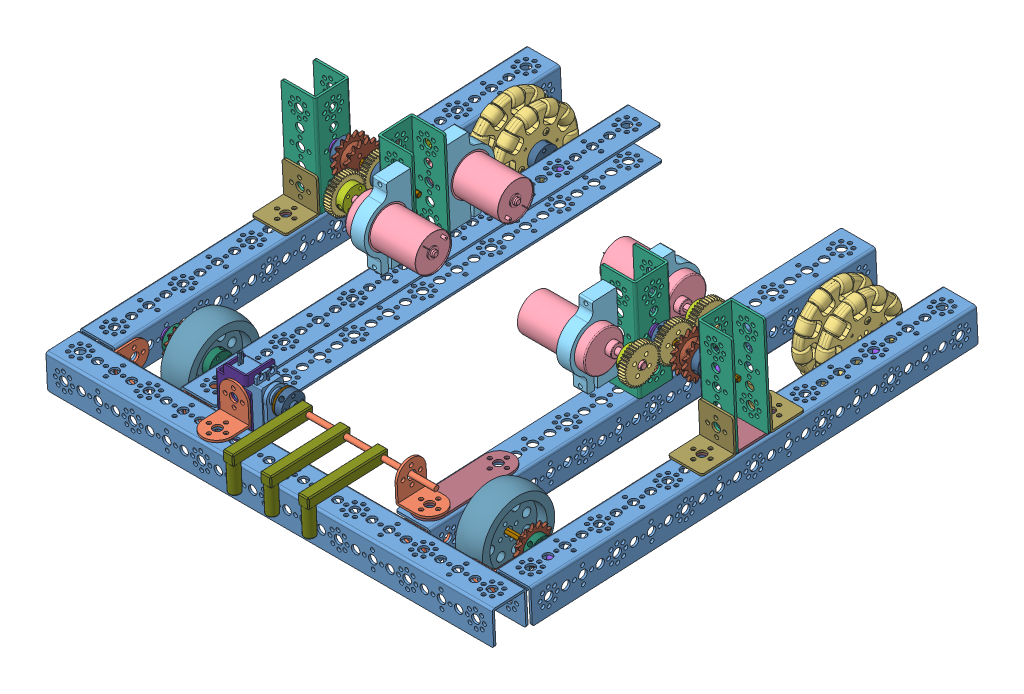
SolidWorks assembly Base Assembly, configuration Default. Lengths in mm.
Overall size (487.76 214.94 471.57).
98 component instances, 22 part files, 130 mates.
Components (placement in the parent):
- Tetrix 416mm-1: Tetrix 416mm [Default] at (441.3728 409.8855 6.1212) x (1 0 0) z (0 -0.047991 0.998848) size (32 32 416)
- Tetrix 416mm-2: Tetrix 416mm [Default] at (347.3728 409.8855 6.1212) x (0 -0.998848 -0.047991) z (0 -0.047991 0.998848) size (32 32 416)
- Tetrix 416mm-3: Tetrix 416mm [Default] at (53.3728 409.8855 6.1212) x (1 0 0) z (0 -0.047991 0.998848) size (32 32 416)
- Tetrix 416mm-4: Tetrix 416mm [Default] at (147.3728 409.8855 6.1212) x (0 0.998848 0.047991) z (0 -0.047991 0.998848) size (32 32 416)
- Tetrix 416mm-5: Tetrix 416mm [Default] at (455.3728 409.0217 24.1004) x (0 0.047991 -0.998848) z (1 0 0) size (32 32 416)
- Tetrix Angle Bracket-1: Tetrix Angle Bracket [Default] at (403.8982 411.5068 -11.8601) x (0 0.998848 0.047991) z (0 -0.047991 0.998848) size (27 31.5 31.5)
- Tetrix Angle Bracket-2: Tetrix Angle Bracket [Default] at (339.8982 411.5068 -11.8601) x (0 0.998848 0.047991) z (0 -0.047991 0.998848) size (27 31.5 31.5)
- Tetrix Angle Bracket-3: Tetrix Angle Bracket [Default] at (90.8475 409.9956 -11.9327) x (0 -0.998848 -0.047991) z (0 -0.047991 0.998848) size (27 31.5 31.5)
- Tetrix Angle Bracket-4: Tetrix Angle Bracket [Default] at (154.8475 409.9956 -11.9327) x (0 -0.998848 -0.047991) z (0 -0.047991 0.998848) size (27 31.5 31.5)
- Base Gearbox-3: Base Gearbox [Default] at (-255.1905 248.791 -250.3559) x (0.93253 -0.360659 -0.017662) z (-0.011317 -0.078079 0.996883) size (179.16 136.45 124.21)
  - Gear Metric 40T-5: Gear Metric 40T [PreviewCfg] at (251.3927 353.961 -2.865) x (0.93253 0.360914 -0.011317) z (-0.302942 0.799028 0.519404) size (6.2 33.53 33.53)
  - Gear Metric 40T-6: Gear Metric 40T [PreviewCfg] at (251.3714 356.0218 61.1018) x (0.93253 0.360914 -0.011317) z (0.242761 -0.649832 -0.720268) size (6.2 33.53 33.53)
  - DC gearhead motor-1: DC gearhead motor [Default] at (298.6742 372.0501 -9.9354) x (0.361091 -0.932043 0.030148) z (0.000333 -0.0322 -0.999481) size (37 98.8 37)
  - DC gearhead motor-2: DC gearhead motor [Default] at (298.6485 374.5295 67.0247) x (-0.361091 0.932043 -0.030148) z (-0.000333 0.0322 0.999481) size (37 98.8 37)
  - Tetrix Motor Mount-5: Tetrix Motor Mount [Default] at (291.2273 357.2311 -9.3463) x (-0.361091 0.932043 -0.030148) z (-0.93253 -0.360914 0.011317) size (72 44.98 12.7)
  - Tetrix Motor Mount-6: Tetrix Motor Mount [Default] at (302.2979 363.9977 67.2511) x (-0.361091 0.932043 -0.030148) z (0.93253 0.360914 -0.011317) size (72 44.98 12.7)
  - Tetrix 96mm-1: Tetrix 96mm [Default] at (302.6119 323.3726 30.1542) x (-0.000333 0.0322 0.999481) z (0.361091 -0.932043 0.030148) size (32 32 96)
  - Hub motor shaft-5: Hub motor shaft [Default] at (257.1744 356.1987 -2.9351) x (-0.196503 0.480932 -0.854454) z (-0.93253 -0.360914 0.011317) size (22 22 9.5)
  - Hub motor shaft-6: Hub motor shaft [Default] at (257.1531 358.2595 61.0317) x (0.267309 -0.668924 0.693604) z (-0.93253 -0.360914 0.011317) size (22 22 9.5)
  - Tetrix 96mm-3: Tetrix 96mm [Default] at (184.0194 380.3664 28.2785) x (-0.000333 0.0322 0.999481) z (-0.361091 0.932043 -0.030148) size (32 32 96)
  - Axle bronze bushing-21: Axle bronze bushing [Default] at (217.5778 341.9083 29.5287) x (0.165216 -0.398599 0.902121) z (0.93253 0.360914 -0.011317) size (11 11 12.4)
  - Axle bronze bushing-22: Axle bronze bushing [Default] at (269.0535 361.8307 28.904) x (0.124395 -0.291672 0.948395) z (-0.93253 -0.360914 0.011317) size (11 11 12.4)
  - Tetrix 4.7mm Axle-14: Tetrix 4.7mm Axle [Default] at (289.9422 369.9152 28.6505) x (0.124395 -0.291672 0.948395) z (-0.93253 -0.360914 0.011317) size (4.7 4.3 100)
  - Gear Metric 40T-17: Gear Metric 40T [PreviewCfg] at (251.3821 354.9914 29.1184) x (0.93253 0.360914 -0.011317) z (0.105307 -0.241847 0.964583) size (6.2 33.53 33.53)
  - Hub axle shaft-27: Hub axle shaft [Default] at (257.1637 357.2291 29.0483) x (0.140118 -0.332797 0.93253) z (-0.93253 -0.360914 0.011317) size (22 22 9.5)
  - Tetrix 16T Sprocket-7: Tetrix 16T Sprocket [Default] at (238.5598 350.0289 29.274) x (0.140118 -0.332797 0.93253) z (-0.93253 -0.360914 0.011317) size (36 36 6.8)
  - Tetrix 16T Sprocket-8: Tetrix 16T Sprocket [Default] at (231.0995 347.1415 29.3646) x (-0.140118 0.332797 -0.93253) z (0.93253 0.360914 -0.011317) size (36 36 6.8)
  - Hub axle shaft-28: Hub axle shaft [Default] at (228.4884 346.131 29.3963) x (0.140118 -0.332797 0.93253) z (0.93253 0.360914 -0.011317) size (22 22 9.5)
  - Tetrix Square Angle Bracket-1: Tetrix Square Angle Bracket [Default] at (212.9174 304.7726 -1.2931) x (-0.93253 -0.360914 0.011317) z (0.000333 -0.0322 -0.999481) size (32 32 32)
  - Tetrix Square Angle Bracket-2: Tetrix Square Angle Bracket [Default] at (212.8961 306.8334 62.6737) x (0.93253 0.360914 -0.011317) z (-0.000333 0.0322 0.999481) size (32 32 32)
  - Bracket flat-1: Bracket flat [Default] at (219.0453 289.9583 31.2028) x (0.000333 -0.0322 -0.999481) z (0.93253 0.360914 -0.011317) size (91 2 27)
  - Tetrix Angle Bracket-13: Tetrix Angle Bracket [Default] at (301.2105 343.7275 30.2548) x (-0.000333 0.0322 0.999481) z (-0.93253 -0.360914 0.011317) size (27 31.5 31.5)
- Base Gearbox-4: Base Gearbox [Default] at (749.9361 244.9085 -169.5482) x (-0.93253 -0.360691 -0.016997) z (0.011317 0.017853 -0.999777) size (179.16 136.45 124.21)
  - Gear Metric 40T-5: Gear Metric 40T [PreviewCfg] at (251.3927 353.961 -2.865) x (0.93253 0.360914 -0.011317) z (-0.302942 0.799028 0.519404) size (6.2 33.53 33.53)
  - Gear Metric 40T-6: Gear Metric 40T [PreviewCfg] at (251.3714 356.0218 61.1018) x (0.93253 0.360914 -0.011317) z (0.242761 -0.649832 -0.720268) size (6.2 33.53 33.53)
  - DC gearhead motor-1: DC gearhead motor [Default] at (298.6742 372.0501 -9.9354) x (0.361091 -0.932043 0.030148) z (0.000333 -0.0322 -0.999481) size (37 98.8 37)
  - DC gearhead motor-2: DC gearhead motor [Default] at (298.6485 374.5295 67.0247) x (-0.361091 0.932043 -0.030148) z (-0.000333 0.0322 0.999481) size (37 98.8 37)
  - Tetrix Motor Mount-5: Tetrix Motor Mount [Default] at (291.2273 357.2311 -9.3463) x (-0.361091 0.932043 -0.030148) z (-0.93253 -0.360914 0.011317) size (72 44.98 12.7)
  - Tetrix Motor Mount-6: Tetrix Motor Mount [Default] at (302.2979 363.9977 67.2511) x (-0.361091 0.932043 -0.030148) z (0.93253 0.360914 -0.011317) size (72 44.98 12.7)
  - Tetrix 96mm-1: Tetrix 96mm [Default] at (302.6119 323.3726 30.1542) x (-0.000333 0.0322 0.999481) z (0.361091 -0.932043 0.030148) size (32 32 96)
  - Hub motor shaft-5: Hub motor shaft [Default] at (257.1744 356.1987 -2.9351) x (-0.196503 0.480932 -0.854454) z (-0.93253 -0.360914 0.011317) size (22 22 9.5)
  - Hub motor shaft-6: Hub motor shaft [Default] at (257.1531 358.2595 61.0317) x (0.267309 -0.668924 0.693604) z (-0.93253 -0.360914 0.011317) size (22 22 9.5)
  - Tetrix 96mm-3: Tetrix 96mm [Default] at (184.0194 380.3664 28.2785) x (-0.000333 0.0322 0.999481) z (-0.361091 0.932043 -0.030148) size (32 32 96)
  - Axle bronze bushing-21: Axle bronze bushing [Default] at (217.5778 341.9083 29.5287) x (0.165216 -0.398599 0.902121) z (0.93253 0.360914 -0.011317) size (11 11 12.4)
  - Axle bronze bushing-22: Axle bronze bushing [Default] at (269.0535 361.8307 28.904) x (0.124395 -0.291672 0.948395) z (-0.93253 -0.360914 0.011317) size (11 11 12.4)
  - Tetrix 4.7mm Axle-14: Tetrix 4.7mm Axle [Default] at (289.9422 369.9152 28.6505) x (0.124395 -0.291672 0.948395) z (-0.93253 -0.360914 0.011317) size (4.7 4.3 100)
  - Gear Metric 40T-17: Gear Metric 40T [PreviewCfg] at (251.3821 354.9914 29.1184) x (0.93253 0.360914 -0.011317) z (0.105307 -0.241847 0.964583) size (6.2 33.53 33.53)
  - Hub axle shaft-27: Hub axle shaft [Default] at (257.1637 357.2291 29.0483) x (0.140118 -0.332797 0.93253) z (-0.93253 -0.360914 0.011317) size (22 22 9.5)
  - Tetrix 16T Sprocket-7: Tetrix 16T Sprocket [Default] at (238.5598 350.0289 29.274) x (0.140118 -0.332797 0.93253) z (-0.93253 -0.360914 0.011317) size (36 36 6.8)
  - Tetrix 16T Sprocket-8: Tetrix 16T Sprocket [Default] at (231.0995 347.1415 29.3646) x (-0.140118 0.332797 -0.93253) z (0.93253 0.360914 -0.011317) size (36 36 6.8)
  - Hub axle shaft-28: Hub axle shaft [Default] at (228.4884 346.131 29.3963) x (0.140118 -0.332797 0.93253) z (0.93253 0.360914 -0.011317) size (22 22 9.5)
  - Tetrix Square Angle Bracket-1: Tetrix Square Angle Bracket [Default] at (212.9174 304.7726 -1.2931) x (-0.93253 -0.360914 0.011317) z (0.000333 -0.0322 -0.999481) size (32 32 32)
  - Tetrix Square Angle Bracket-2: Tetrix Square Angle Bracket [Default] at (212.8961 306.8334 62.6737) x (0.93253 0.360914 -0.011317) z (-0.000333 0.0322 0.999481) size (32 32 32)
  - Bracket flat-1: Bracket flat [Default] at (219.0453 289.9583 31.2028) x (0.000333 -0.0322 -0.999481) z (0.93253 0.360914 -0.011317) size (91 2 27)
  - Tetrix Angle Bracket-13: Tetrix Angle Bracket [Default] at (301.2105 343.7275 30.2548) x (-0.000333 0.0322 0.999481) z (-0.93253 -0.360914 0.011317) size (27 31.5 31.5)
- Wheel 76mm 3-in-1: Wheel 76mm 3-in [Default] at (374.1068 412.1891 -41.8235) x (0 0.924225 0.381849) z (-1 0 0) size (72.2 72.2 25.4)
- Axle bronze bushing-1: Axle bronze bushing [Default] at (364.7728 426.7783 -345.4732) x (0 0 -1) z (1 0 0) size (11 11 12.4)
- Tetrix 4.7mm Axle Hub-1: Tetrix 4.7mm Axle Hub [Default] at (412.2728 412.1891 -41.8235) x (0 0 1) z (-1 0 0) size (22 22 9.4)
- Tetrix 4.7mm Axle Hub-2: Tetrix 4.7mm Axle Hub [Default] at (82.4728 412.1891 -41.8235) x (0 0 -1) z (1 0 0) size (22 22 9.4)
- Tetrix 4.7mm Axle Hub-3: Tetrix 4.7mm Axle Hub [Default] at (381.4728 412.1891 -41.8235) x (0 0.924225 0.381849) z (1 0 0) size (22 22 9.4)
- Tetrix 4.7mm Axle Hub-4: Tetrix 4.7mm Axle Hub [Default] at (113.2728 412.1891 -41.8235) x (0 0.924225 0.381849) z (-1 0 0) size (22 22 9.4)
- Tetrix 4.7mm Axle-1: Tetrix 4.7mm Axle [Default] at (346.3728 426.7783 -345.4732) x (0 0 -1) z (1 0 0) size (4.7 4.3 100)
- Tetrix 4.7mm Axle-2: Tetrix 4.7mm Axle [Default] at (48.3728 426.7783 -345.4732) x (0 0 -1) z (1 0 0) size (4.7 4.3 100)
- Tetrix 4.7mm Axle-3: Tetrix 4.7mm Axle [Default] at (48.3728 412.1891 -41.8235) x (0 0 -1) z (1 0 0) size (4.7 4.3 100)
- Tetrix 4.7mm Axle-4: Tetrix 4.7mm Axle [Default] at (446.3728 412.1891 -41.8235) x (0 0 1) z (-1 0 0) size (4.7 4.3 100)
- Axle bronze bushing-2: Axle bronze bushing [Default] at (70.7728 412.1891 -41.8235) x (0 0 -1) z (1 0 0) size (11 11 12.4)
- Axle bronze bushing-3: Axle bronze bushing [Default] at (423.9728 426.7783 -345.4732) x (0 0 1) z (-1 0 0) size (11 11 12.4)
- Axle bronze bushing-4: Axle bronze bushing [Default] at (423.9728 412.1891 -41.8235) x (0 0 1) z (-1 0 0) size (11 11 12.4)
- Axle bronze bushing-5: Axle bronze bushing [Default] at (129.9728 412.1891 -41.8235) x (0 0 1) z (-1 0 0) size (11 11 12.4)
- Axle bronze bushing-6: Axle bronze bushing [Default] at (70.7728 426.7783 -345.4732) x (0 0 -1) z (1 0 0) size (11 11 12.4)
- Axle bronze bushing-7: Axle bronze bushing [Default] at (364.7728 412.1891 -41.8235) x (0 0 -1) z (1 0 0) size (11 11 12.4)
- Axle bronze bushing-8: Axle bronze bushing [Default] at (129.9728 426.7783 -345.4732) x (0 0 1) z (-1 0 0) size (11 11 12.4)
- Wheel 76mm 3-in-2: Wheel 76mm 3-in [Default] at (99.5568 412.1891 -41.8235) x (0 0.381849 -0.924225) z (-1 0 0) size (72.2 72.2 25.4)
- Tetrix 16T Sprocket-2: Tetrix 16T Sprocket [Default] at (409.4728 412.1891 -41.8235) x (0 0 1) z (-1 0 0) size (36 36 6.8)
- Tetrix 16T Sprocket-4: Tetrix 16T Sprocket [Default] at (85.2728 412.1891 -41.8235) x (0 0 -1) z (1 0 0) size (36 36 6.8)
- Goal Hook-1: Goal Hook [Default] at (234.3728 451.6043 -13.5212) x (0 0.043619 -0.999048) z (-1 0 0) size (75 35 10)
- Goal Hook-2: Goal Hook [Default] at (304.3728 451.6043 -13.5212) x (0 0.043619 -0.999048) z (-1 0 0) size (75 35 10)
- Goal Hook-3: Goal Hook [Default] at (269.3728 451.6043 -13.5212) x (0 0.043619 -0.999048) z (-1 0 0) size (75 35 10)
- Bracket servo single-1: Bracket servo single [Default] at (183.3728 435.8556 7.3689) x (0 -0.998848 -0.047991) z (1 0 0) size (60 26.6 32.67)
- Servo metal horn-1: Servo metal horn [Default] at (211.7728 446.391 -8.744) x (0 -1 0) z (0 0 1) size (22.2 6.2 22.2)
- Servo motor HS475-1: Servo motor HS475 [Default] at (193.9728 446.391 -8.744) x (0 -0.047991 0.998848) z (0 0.998848 0.047991) size (20 43.2 56.6)
- Hub axle shaft-5: Hub axle shaft [Default] at (220.4728 446.391 -8.744) x (0 0 -1) z (1 0 0) size (22 22 9.5)
- Axle D-shaft-1: Axle D-shaft [Default] at (283.7728 446.391 -8.744) x (0 0.043619 -0.999048) z (-1 0 0) size (4.73 4.46 140)
- Tetrix Angle Bracket-6: Tetrix Angle Bracket [Default] at (182.6164 446.3553 27.9349) x (-1 0 0) z (0 0.047991 -0.998848) size (27 31.5 31.5)
- Tetrix Angle Bracket-7: Tetrix Angle Bracket [Default] at (349.4112 450.0462 -7.2104) x (0 -0.047991 0.998848) z (-1 0 0) size (27 31.5 31.5)
- Bracket flat-1: Bracket flat [Default] at (347.3728 429.1695 -41.0077) x (0 -0.047991 0.998848) z (-1 0 0) size (91 2 27)
- Omni Wheels-1: Omni Wheels [Default] at (39.7243 394.7419 -398.5232) x (0 -0.381849 0.924225) z (0 0.924225 0.381849) size (77.7 40.21 77.72)
  - 3-inch omni single wheel part-1: 3-inch omni single wheel part [Default] at (43.8688 43.474 49.8315) size (77.7 13.48 77.72)
  - 3-inch omni single wheel part-2: 3-inch omni single wheel part [Default] at (43.8688 71.023 49.9004) x (1 0 0) z (0 0 -1) size (77.7 13.48 77.72)
  - Omni wheel joining hub-1: Omni wheel joining hub [Default] at (36.7969 53.8485 49.866) x (1 0 0) z (0 1 0) size (22 22 5)
  - Tetrix 16T Sprocket-1: Tetrix 16T Sprocket [Default] at (36.7969 59.1485 49.866) x (0.987505 0 -0.157585) z (0 1 0) size (36 36 6.8)
  - Hub axle shaft-1: Hub axle shaft [Default] at (36.7969 73.1485 49.866) x (0.987505 0 0.157585) z (0 -1 0) size (22 22 9.5)
- Omni Wheels-2: Omni Wheels [Default] at (457.8214 389.9814 -395.3392) x (0 1 0) z (0 0 1) size (77.7 40.21 77.72)
  - 3-inch omni single wheel part-1: 3-inch omni single wheel part [Default] at (43.8688 43.474 49.8315) size (77.7 13.48 77.72)
  - 3-inch omni single wheel part-2: 3-inch omni single wheel part [Default] at (43.8688 71.023 49.9004) x (1 0 0) z (0 0 -1) size (77.7 13.48 77.72)
  - Omni wheel joining hub-1: Omni wheel joining hub [Default] at (36.7969 53.8485 49.866) x (1 0 0) z (0 1 0) size (22 22 5)
  - Tetrix 16T Sprocket-1: Tetrix 16T Sprocket [Default] at (36.7969 59.1485 49.866) x (0.987505 0 -0.157585) z (0 1 0) size (36 36 6.8)
  - Hub axle shaft-1: Hub axle shaft [Default] at (36.7969 73.1485 49.866) x (0.987505 0 0.157585) z (0 -1 0) size (22 22 9.5)
Mates (geometry in assembly coordinates):
- Coincident1: coincident anti-aligned: plane of Tetrix 416mm-5 through (39.3728 425.7711 8.8867) normal (0 0.047991 -0.998848); plane of Tetrix Angle Bracket-1 through (393.8728 396.3051 7.471) normal (0 -0.047991 0.998848)
- Concentric1: concentric anti-aligned: cylinder of Tetrix 416mm-5 through (407.3728 408.2538 40.082) axis (0 0.047991 -0.998848) radius 4; cylinder of Tetrix Angle Bracket-1 through (407.3728 411.3013 -23.3448) axis (0 -0.047991 0.998848) radius 4
- Concentric2: concentric anti-aligned: cylinder of Tetrix 416mm-5 through (415.3728 408.2538 40.082) axis (0 0.047991 -0.998848) radius 1.85; cylinder of Tetrix Angle Bracket-1 through (415.3728 411.3013 -23.3448) axis (0 -0.047991 0.998848) radius 1.85
- Coincident2: coincident anti-aligned: plane of Tetrix 416mm-1 through (425.3728 445.8313 -408.6316) normal (-1 0 0); plane of Tetrix Angle Bracket-1 through (425.3728 396.3051 7.471) normal (1 0 0)
- Concentric3: concentric aligned: cylinder of Tetrix 416mm-1 through (425.3728 410.6534 -9.8604) axis (1 0 0) radius 4; cylinder of Tetrix Angle Bracket-1 through (393.8728 410.6534 -9.8604) axis (1 0 0) radius 4
- Concentric4: concentric aligned: cylinder of Tetrix 416mm-1 through (425.3728 411.0373 -17.8512) axis (1 0 0) radius 1.85; cylinder of Tetrix Angle Bracket-1 through (393.8728 411.0373 -17.8512) axis (1 0 0) radius 1.85
- Coincident5: coincident anti-aligned: plane of Tetrix 416mm-5 through (39.3728 425.7711 8.8867) normal (0 0.047991 -0.998848); plane of Tetrix Angle Bracket-2 through (329.8728 396.3051 7.471) normal (0 -0.047991 0.998848)
- Concentric11: concentric anti-aligned: cylinder of Tetrix 416mm-5 through (335.3728 408.2538 40.082) axis (0 0.047991 -0.998848) radius 1.85; cylinder of Tetrix Angle Bracket-2 through (335.3728 411.3013 -23.3448) axis (0 -0.047991 0.998848) radius 1.85
- Concentric13: concentric anti-aligned: cylinder of Tetrix 416mm-5 through (351.3728 408.2538 40.082) axis (0 0.047991 -0.998848) radius 1.85; cylinder of Tetrix Angle Bracket-2 through (351.3728 411.3013 -23.3448) axis (0 -0.047991 0.998848) radius 1.85
- Coincident6: coincident anti-aligned: plane of Tetrix 416mm-2 through (361.3728 443.8336 -408.7276) normal (-1 0 0); plane of Tetrix Angle Bracket-2 through (361.3728 396.3051 7.471) normal (1 0 0)
- Concentric14: concentric aligned: cylinder of Tetrix 416mm-2 through (331.3728 402.6626 -10.2443) axis (1 0 0) radius 1.85; cylinder of Tetrix Angle Bracket-2 through (329.8728 402.6626 -10.2443) axis (1 0 0) radius 1.85
- Concentric15: concentric aligned: cylinder of Tetrix 416mm-2 through (331.3728 418.6442 -9.4765) axis (1 0 0) radius 1.85; cylinder of Tetrix Angle Bracket-2 through (329.8728 418.6442 -9.4765) axis (1 0 0) radius 1.85
- Coincident7: coincident anti-aligned: plane of Tetrix 416mm-5 through (39.3728 425.7711 8.8867) normal (0 0.047991 -0.998848); plane of Tetrix Angle Bracket-3 through (100.8728 423.274 8.7667) normal (0 -0.047991 0.998848)
- Concentric16: concentric anti-aligned: cylinder of Tetrix 416mm-5 through (87.3728 408.2538 40.082) axis (0 0.047991 -0.998848) radius 4; cylinder of Tetrix Angle Bracket-3 through (87.3728 411.3013 -23.3448) axis (0 -0.047991 0.998848) radius 4
- Concentric17: concentric anti-aligned: cylinder of Tetrix 416mm-5 through (87.3728 416.2446 40.4659) axis (0 0.047991 -0.998848) radius 1.85; cylinder of Tetrix Angle Bracket-3 through (87.3728 419.292 -22.9609) axis (0 -0.047991 0.998848) radius 1.85
- Coincident8: coincident anti-aligned: plane of Tetrix 416mm-3 through (69.3728 445.8313 -408.6316) normal (1 0 0); plane of Tetrix Angle Bracket-3 through (69.3728 423.274 8.7667) normal (-1 0 0)
- Concentric18: concentric anti-aligned: cylinder of Tetrix 416mm-3 through (37.3728 410.6534 -9.8604) axis (1 0 0) radius 4; cylinder of Tetrix Angle Bracket-3 through (100.8728 410.6534 -9.8604) axis (-1 0 0) radius 4
- Concentric19: concentric anti-aligned: cylinder of Tetrix 416mm-3 through (37.3728 411.0373 -17.8512) axis (1 0 0) radius 1.85; cylinder of Tetrix Angle Bracket-3 through (100.8728 411.0373 -17.8512) axis (-1 0 0) radius 1.85
- Concentric21: concentric anti-aligned: cylinder of Tetrix 416mm-3 through (37.3728 410.2695 -1.8696) axis (1 0 0) radius 1.85; cylinder of Tetrix Angle Bracket-3 through (100.8728 410.2695 -1.8696) axis (-1 0 0) radius 1.85
- Coincident9: coincident anti-aligned: plane of Tetrix 416mm-5 through (39.3728 425.7711 8.8867) normal (0 0.047991 -0.998848); plane of Tetrix Angle Bracket-4 through (164.8728 423.274 8.7667) normal (0 -0.047991 0.998848)
- Concentric22: concentric anti-aligned: cylinder of Tetrix 416mm-5 through (151.3728 408.2538 40.082) axis (0 0.047991 -0.998848) radius 4; cylinder of Tetrix Angle Bracket-4 through (151.3728 411.3013 -23.3448) axis (0 -0.047991 0.998848) radius 4
- Concentric23: concentric anti-aligned: cylinder of Tetrix 416mm-5 through (143.3728 408.2538 40.082) axis (0 0.047991 -0.998848) radius 1.85; cylinder of Tetrix Angle Bracket-4 through (143.3728 411.3013 -23.3448) axis (0 -0.047991 0.998848) radius 1.85
- Coincident10: coincident anti-aligned: plane of Tetrix 416mm-4 through (133.3728 415.8659 -410.0714) normal (1 0 0); plane of Tetrix Angle Bracket-4 through (133.3728 423.274 8.7667) normal (-1 0 0)
- Concentric24: concentric aligned: cylinder of Tetrix 416mm-4 through (163.3728 410.6534 -9.8604) axis (-1 0 0) radius 4; cylinder of Tetrix Angle Bracket-4 through (164.8728 410.6534 -9.8604) axis (-1 0 0) radius 4
- Concentric25: concentric aligned: cylinder of Tetrix 416mm-4 through (163.3728 410.2695 -1.8696) axis (-1 0 0) radius 1.85; cylinder of Tetrix Angle Bracket-4 through (164.8728 410.2695 -1.8696) axis (-1 0 0) radius 1.85
- Coincident16: coincident anti-aligned: plane of Tetrix 416mm-3 through (43.0826 314.0125 -449.5638) normal (0 0.998848 0.047991); plane of ? through (77.0826 302.6146 -212.3374) normal (0 -0.998848 -0.047991)
- Concentric36: concentric anti-aligned: cylinder of Tetrix 416mm-3 through (59.0826 270.9154 -219.3668) axis (0 0.998848 0.047991) radius 1.85; cylinder of ? through (59.0826 334.3423 -216.3194) axis (0 -0.998848 -0.047991) radius 1.85
- Concentric37: concentric anti-aligned: cylinder of Tetrix 416mm-3 through (59.0826 271.6833 -235.3484) axis (0 0.998848 0.047991) radius 1.85; cylinder of ? through (59.0826 335.1101 -232.301) axis (0 -0.998848 -0.047991) radius 1.85
- Concentric38: concentric anti-aligned: cylinder of Tetrix 416mm-4 through (153.0826 270.9154 -219.3668) axis (0 0.998848 0.047991) radius 1.85; cylinder of ? through (153.0826 334.3423 -216.3194) axis (0 -0.998848 -0.047991) radius 1.85
- Concentric39: concentric anti-aligned: cylinder of Tetrix 416mm-4 through (153.0826 271.6833 -235.3484) axis (0 0.998848 0.047991) radius 1.85; cylinder of ? through (153.0826 335.1101 -232.301) axis (0 -0.998848 -0.047991) radius 1.85
- Coincident17: coincident anti-aligned: plane of Tetrix 416mm-1 through (431.0826 314.0125 -449.5638) normal (0 0.998848 0.047991); plane of ? through (429.0826 303.9104 -239.3063) normal (0 -0.998848 -0.047991)
- Concentric40: concentric aligned: cylinder of Tetrix 416mm-2 through (353.0826 303.2625 -225.8219) axis (0 -0.998848 -0.047991) radius 4; cylinder of ? through (353.0826 334.7262 -224.3102) axis (0 -0.998848 -0.047991) radius 4
- Concentric42: concentric aligned: cylinder of Tetrix 416mm-2 through (353.0826 302.8786 -217.8311) axis (0 -0.998848 -0.047991) radius 1.85; cylinder of ? through (353.0826 334.3423 -216.3194) axis (0 -0.998848 -0.047991) radius 1.85
- Concentric43: concentric anti-aligned: cylinder of Tetrix 416mm-1 through (447.0826 270.9154 -219.3668) axis (0 0.998848 0.047991) radius 1.85; cylinder of ? through (447.0826 334.3423 -216.3194) axis (0 -0.998848 -0.047991) radius 1.85
- Concentric44: concentric anti-aligned: cylinder of Tetrix 416mm-1 through (447.0826 271.6833 -235.3484) axis (0 0.998848 0.047991) radius 1.85; cylinder of ? through (447.0826 335.1101 -232.301) axis (0 -0.998848 -0.047991) radius 1.85
- Concentric45: concentric anti-aligned: cylinder of Tetrix 4.7mm Axle Hub-1 through (409.5728 412.1891 -41.8235) axis (1 0 0) radius 3.9625; cylinder of Tetrix 16T Sprocket-2 through (412.2728 412.1891 -41.8235) axis (-1 0 0) radius 4
- Coincident19: coincident anti-aligned: plane of Tetrix 4.7mm Axle Hub-1 through (412.2728 412.1891 -41.8235) normal (-1 0 0); plane of Tetrix 16T Sprocket-2 through (412.2728 428.4641 -41.8235) normal (1 0 0)
- Concentric46: concentric aligned: cylinder of Tetrix 4.7mm Axle Hub-1 through (418.9728 420.1891 -41.8235) axis (-1 0 0) radius 1.35; cylinder of Tetrix 16T Sprocket-2 through (412.2728 420.1891 -41.8235) axis (-1 0 0) radius 1.8
- Coincident20: coincident anti-aligned: plane of Tetrix 4.7mm Axle Hub-2 through (82.4728 412.1891 -41.8235) normal (1 0 0); plane of Tetrix 16T Sprocket-4 through (82.4728 428.4641 -41.8235) normal (-1 0 0)
- Concentric47: concentric anti-aligned: cylinder of Tetrix 4.7mm Axle Hub-2 through (85.1728 412.1891 -41.8235) axis (-1 0 0) radius 3.9625; cylinder of Tetrix 16T Sprocket-4 through (82.4728 412.1891 -41.8235) axis (1 0 0) radius 4
- Concentric48: concentric aligned: cylinder of Tetrix 4.7mm Axle Hub-2 through (75.7728 420.1891 -41.8235) axis (1 0 0) radius 1.35; cylinder of Tetrix 16T Sprocket-4 through (82.4728 420.1891 -41.8235) axis (1 0 0) radius 1.8
- Concentric49: concentric aligned: cylinder of Tetrix 416mm-2 through (331.3728 412.1891 -41.8235) axis (1 0 0) radius 4; cylinder of Axle bronze bushing-7 through (352.3728 412.1891 -41.8235) axis (1 0 0) radius 3.925
- Coincident21: coincident anti-aligned: plane of Tetrix 416mm-2 through (363.3728 445.8313 -408.6316) normal (1 0 0); plane of Axle bronze bushing-7 through (363.3728 412.1891 -41.8235) normal (-1 0 0)
- Concentric50: concentric anti-aligned: cylinder of Tetrix 416mm-1 through (425.3728 412.1891 -41.8235) axis (1 0 0) radius 4; cylinder of Axle bronze bushing-4 through (436.3728 412.1891 -41.8235) axis (-1 0 0) radius 3.925
- Coincident22: coincident anti-aligned: plane of Tetrix 416mm-1 through (425.3728 445.8313 -408.6316) normal (-1 0 0); plane of Axle bronze bushing-4 through (425.3728 412.1891 -41.8235) normal (1 0 0)
- Concentric51: concentric anti-aligned: cylinder of Tetrix 4.7mm Axle-4 through (346.3728 412.1891 -41.8235) axis (1 0 0) radius 2.35; cylinder of Axle bronze bushing-4 through (436.3728 412.1891 -41.8235) axis (-1 0 0) radius 2.4
- Distance1: distance = 10 mm aligned: plane of Tetrix 4.7mm Axle-4 through (446.3728 412.1891 -41.8235) normal (1 0 0); plane of Axle bronze bushing-4 through (436.3728 412.1891 -41.8235) normal (1 0 0)
- Coincident24: coincident anti-aligned: plane of Wheel 76mm 3-in-1 through (376.4728 412.1891 -41.8235) normal (-1 0 0); plane of Tetrix 4.7mm Axle Hub-3 through (376.4728 412.1891 -41.8235) normal (1 0 0)
- Concentric52: concentric aligned: cylinder of Wheel 76mm 3-in-1 through (392.3478 412.1891 -41.8235) axis (-1 0 0) radius 4; cylinder of Tetrix 4.7mm Axle Hub-3 through (379.1728 412.1891 -41.8235) axis (-1 0 0) radius 3.9625
- Concentric53: concentric anti-aligned: cylinder of Tetrix 4.7mm Axle Hub-4 through (110.5728 412.1891 -41.8235) axis (1 0 0) radius 3.9625; cylinder of Wheel 76mm 3-in-2 through (122.7978 412.1891 -41.8235) axis (-1 0 0) radius 4
- Coincident25: coincident anti-aligned: plane of Tetrix 4.7mm Axle Hub-4 through (113.2728 412.1891 -41.8235) normal (-1 0 0); plane of Wheel 76mm 3-in-2 through (113.2728 412.1891 -41.8235) normal (1 0 0)
- Concentric54: concentric aligned: cylinder of Tetrix 4.7mm Axle Hub-4 through (119.9728 415.2439 -49.2173) axis (-1 0 0) radius 1.35; cylinder of Wheel 76mm 3-in-2 through (122.7978 415.2439 -49.2173) axis (-1 0 0) radius 1.75
- Concentric55: concentric anti-aligned: cylinder of Wheel 76mm 3-in-1 through (392.3478 415.2439 -49.2173) axis (-1 0 0) radius 1.75; cylinder of Tetrix 4.7mm Axle Hub-3 through (369.7728 415.2439 -49.2173) axis (1 0 0) radius 1.35
- Distance4: distance = 10 mm anti-aligned: plane of Tetrix 4.7mm Axle Hub-3 through (374.7728 412.1891 -41.8235) normal (-1 0 0); plane of Axle bronze bushing-7 through (364.7728 412.1891 -41.8235) normal (1 0 0)
- Concentric58: concentric aligned: cylinder of Tetrix 4.7mm Axle Hub-3 through (369.7728 412.1891 -41.8235) axis (1 0 0) radius 2.365; cylinder of Tetrix 4.7mm Axle-4 through (346.3728 412.1891 -41.8235) axis (1 0 0) radius 2.35
- Concentric59: concentric anti-aligned: cylinder of Tetrix 4.7mm Axle Hub-1 through (418.9728 412.1891 -41.8235) axis (-1 0 0) radius 2.365; cylinder of Tetrix 4.7mm Axle-4 through (346.3728 412.1891 -41.8235) axis (1 0 0) radius 2.35
- Coincident29: coincident aligned: plane of ? through (418.6326 400.6307 -226.9639) normal (1 0 0); plane of Tetrix 16T Sprocket-2 through (418.6326 296.6452 -82.7557) normal (1 0 0)
- Concentric60: concentric aligned: cylinder of Tetrix 416mm-3 through (37.3728 412.1891 -41.8235) axis (1 0 0) radius 4; cylinder of Axle bronze bushing-2 through (58.3728 412.1891 -41.8235) axis (1 0 0) radius 3.925
- Coincident30: coincident anti-aligned: plane of Tetrix 416mm-3 through (69.3728 445.8313 -408.6316) normal (1 0 0); plane of Axle bronze bushing-2 through (69.3728 412.1891 -41.8235) normal (-1 0 0)
- Concentric61: concentric aligned: cylinder of Tetrix 416mm-4 through (163.3728 412.1891 -41.8235) axis (-1 0 0) radius 4; cylinder of Axle bronze bushing-5 through (142.3728 412.1891 -41.8235) axis (-1 0 0) radius 3.925
- Coincident31: coincident anti-aligned: plane of Tetrix 416mm-4 through (131.3728 413.8682 -410.1674) normal (-1 0 0); plane of Axle bronze bushing-5 through (131.3728 412.1891 -41.8235) normal (1 0 0)
- Concentric62: concentric anti-aligned: cylinder of Tetrix 4.7mm Axle-3 through (148.3728 412.1891 -41.8235) axis (-1 0 0) radius 2.35; cylinder of Axle bronze bushing-2 through (58.3728 412.1891 -41.8235) axis (1 0 0) radius 2.4
- Distance5: distance = 10 mm aligned: plane of Tetrix 4.7mm Axle-3 through (48.3728 412.1891 -41.8235) normal (-1 0 0); plane of Axle bronze bushing-2 through (58.3728 412.1891 -41.8235) normal (-1 0 0)
- Distance6: distance = 10 mm anti-aligned: plane of Tetrix 4.7mm Axle Hub-4 through (119.9728 412.1891 -41.8235) normal (1 0 0); plane of Axle bronze bushing-5 through (129.9728 412.1891 -41.8235) normal (-1 0 0)
- Concentric64: concentric aligned: cylinder of Tetrix 4.7mm Axle Hub-4 through (119.9728 412.1891 -41.8235) axis (-1 0 0) radius 2.365; cylinder of Tetrix 4.7mm Axle-3 through (148.3728 412.1891 -41.8235) axis (-1 0 0) radius 2.35
- Concentric65: concentric anti-aligned: cylinder of Tetrix 4.7mm Axle-3 through (148.3728 412.1891 -41.8235) axis (-1 0 0) radius 2.35; cylinder of Tetrix 16T Sprocket-4 through (82.4728 412.1891 -41.8235) axis (1 0 0) radius 4
- Coincident35: coincident aligned: plane of ? through (90.3326 389.747 -219.8785) normal (1 0 0); plane of Tetrix 16T Sprocket-4 through (90.3326 285.3702 -82.7557) normal (1 0 0)
- Concentric76: concentric aligned: cylinder of Tetrix 416mm-3 through (37.3728 426.7783 -345.4732) axis (1 0 0) radius 4; cylinder of Axle bronze bushing-6 through (58.3728 426.7783 -345.4732) axis (1 0 0) radius 3.925
- Coincident39: coincident anti-aligned: plane of Tetrix 416mm-3 through (69.3728 445.8313 -408.6316) normal (1 0 0); plane of Axle bronze bushing-6 through (69.3728 426.7783 -345.4732) normal (-1 0 0)
- Concentric77: concentric aligned: cylinder of Tetrix 416mm-4 through (163.3728 426.7783 -345.4732) axis (-1 0 0) radius 4; cylinder of Axle bronze bushing-8 through (142.3728 426.7783 -345.4732) axis (-1 0 0) radius 3.925
- Coincident40: coincident anti-aligned: plane of Tetrix 416mm-4 through (131.3728 413.8682 -410.1674) normal (-1 0 0); plane of Axle bronze bushing-8 through (131.3728 426.7783 -345.4732) normal (1 0 0)
- Concentric78: concentric anti-aligned: cylinder of Tetrix 4.7mm Axle-2 through (148.3728 426.7783 -345.4732) axis (-1 0 0) radius 2.35; cylinder of Axle bronze bushing-6 through (58.3728 426.7783 -345.4732) axis (1 0 0) radius 2.4
- Distance7: distance = 10 mm aligned: plane of Tetrix 4.7mm Axle-2 through (48.3728 426.7783 -345.4732) normal (-1 0 0); plane of Axle bronze bushing-6 through (58.3728 426.7783 -345.4732) normal (-1 0 0)
- Concentric88: concentric aligned: cylinder of Tetrix 416mm-2 through (331.3728 426.7783 -345.4732) axis (1 0 0) radius 4; cylinder of Axle bronze bushing-1 through (352.3728 426.7783 -345.4732) axis (1 0 0) radius 3.925
- Coincident48: coincident anti-aligned: plane of Tetrix 416mm-2 through (363.3728 445.8313 -408.6316) normal (1 0 0); plane of Axle bronze bushing-1 through (363.3728 426.7783 -345.4732) normal (-1 0 0)
- Concentric89: concentric anti-aligned: cylinder of Tetrix 416mm-1 through (425.3728 426.7783 -345.4732) axis (1 0 0) radius 4; cylinder of Axle bronze bushing-3 through (436.3728 426.7783 -345.4732) axis (-1 0 0) radius 3.925
- Coincident49: coincident anti-aligned: plane of Tetrix 416mm-1 through (425.3728 445.8313 -408.6316) normal (-1 0 0); plane of Axle bronze bushing-3 through (425.3728 426.7783 -345.4732) normal (1 0 0)
- Concentric90: concentric anti-aligned: cylinder of Axle bronze bushing-1 through (352.3728 426.7783 -345.4732) axis (1 0 0) radius 2.4; cylinder of Tetrix 4.7mm Axle-1 through (446.3728 426.7783 -345.4732) axis (-1 0 0) radius 2.35
- Distance10: distance = 10 mm aligned: plane of Tetrix 4.7mm Axle-1 through (446.3728 426.7783 -345.4732) normal (1 0 0); plane of Axle bronze bushing-3 through (436.3728 426.7783 -345.4732) normal (1 0 0)
- Coincident62: coincident anti-aligned: plane of Bracket servo single-1 through (193.9728 405.9669 4.3311) normal (1 0 0); plane of Servo motor HS475-1 through (193.9728 410.9535 -2.5626) normal (-1 0 0)
- Concentric103: concentric anti-aligned: cylinder of Bracket servo single-1 through (193.9728 460.6148 -13.0664) axis (1 0 0) radius 1.85; cylinder of Servo motor HS475-1 through (196.4728 460.6148 -13.0664) axis (-1 0 0) radius 2.15
- Concentric104: concentric anti-aligned: cylinder of Bracket servo single-1 through (193.9728 460.1349 -3.0779) axis (1 0 0) radius 1.85; cylinder of Servo motor HS475-1 through (196.4728 460.1349 -3.0779) axis (-1 0 0) radius 2.15
- Coincident63: coincident anti-aligned: plane of Bracket servo single-1 through (193.9728 405.9669 4.3311) normal (1 0 0); plane of Servo motor HS475-1 through (193.9728 410.9535 -2.5626) normal (-1 0 0)
- Concentric111: concentric aligned: cylinder of Servo metal horn-1 through (210.5728 446.391 -8.744) axis (-1 0 0) radius 2.85; cylinder of Servo motor HS475-1 through (210.5728 446.391 -8.744) axis (-1 0 0) radius 3
- Coincident65: coincident anti-aligned: plane of Servo metal horn-1 through (210.5728 446.391 -8.744) normal (-1 0 0); plane of Servo motor HS475-1 through (210.5728 446.391 -8.744) normal (1 0 0)
- Coincident66: coincident anti-aligned: plane of Servo metal horn-1 through (213.7728 446.391 -8.744) normal (1 0 0); plane of Hub axle shaft-5 through (213.7728 446.391 -8.744) normal (-1 0 0)
- Concentric113: concentric anti-aligned: cylinder of Servo metal horn-1 through (213.7728 446.391 -8.744) axis (-1 0 0) radius 1.75; cylinder of Hub axle shaft-5 through (213.7728 446.391 -8.744) axis (1 0 0) radius 2.3495
- Concentric116: concentric aligned: cylinder of Servo metal horn-1 through (211.7728 454.391 -8.744) axis (1 0 0) radius 1.75; cylinder of Hub axle shaft-5 through (220.4728 454.391 -8.744) axis (1 0 0) radius 1.3526
- Distance13: distance = 25 mm anti-aligned: plane of Goal Hook-3 through (269.3728 441.6138 -13.9574) normal (1 0 0); plane of Goal Hook-2 through (294.3728 441.6138 -13.9574) normal (-1 0 0)
- Distance14: distance = 25 mm anti-aligned: plane of Goal Hook-3 through (259.3728 441.6138 -13.9574) normal (-1 0 0); plane of Goal Hook-1 through (234.3728 441.6138 -13.9574) normal (1 0 0)
- Coincident71: coincident anti-aligned: plane of Servo metal horn-1 through (213.7728 446.391 -8.744) normal (1 0 0); plane of Axle D-shaft-1 through (213.7728 446.391 -8.744) normal (-1 0 0)
- Concentric121: concentric anti-aligned: cylinder of Hub axle shaft-5 through (213.7728 446.391 -8.744) axis (1 0 0) radius 2.3495; cylinder of Axle D-shaft-1 through (353.7728 446.391 -8.744) axis (-1 0 0) radius 2.365
- Concentric122: concentric aligned: cylinder of Goal Hook-2 through (304.3728 446.391 -8.744) axis (-1 0 0) radius 2.35; cylinder of Axle D-shaft-1 through (353.7728 446.391 -8.744) axis (-1 0 0) radius 2.365
- Concentric123: concentric aligned: cylinder of Goal Hook-3 through (269.3728 446.391 -8.744) axis (-1 0 0) radius 2.35; cylinder of Axle D-shaft-1 through (353.7728 446.391 -8.744) axis (-1 0 0) radius 2.365
- Coincident74: coincident anti-aligned: plane of Tetrix 416mm-5 through (39.3728 424.2354 40.8499) normal (0 0.998848 0.047991); plane of Tetrix Angle Bracket-6 through (196.8728 425.8671 6.889) normal (0 -0.998848 -0.047991)
- Concentric127: concentric anti-aligned: cylinder of Tetrix 416mm-5 through (183.3728 393.0401 23.3326) axis (0 0.998848 0.047991) radius 4; cylinder of Tetrix Angle Bracket-6 through (183.3728 456.467 26.38) axis (0 -0.998848 -0.047991) radius 4
- Concentric128: concentric anti-aligned: cylinder of Tetrix 416mm-5 through (183.3728 392.6562 31.3234) axis (0 0.998848 0.047991) radius 1.85; cylinder of Tetrix Angle Bracket-6 through (183.3728 456.083 34.3708) axis (0 -0.998848 -0.047991) radius 1.85
- Coincident75: coincident anti-aligned: plane of Bracket servo single-1 through (193.9728 418.3757 6.5291) normal (0 -0.047991 0.998848); plane of Tetrix Angle Bracket-6 through (196.8728 457.3308 8.4007) normal (0 0.047991 -0.998848)
- Concentric131: concentric aligned: cylinder of Tetrix 416mm-2 through (339.3728 426.6349 -9.0925) axis (0 -0.998848 -0.047991) radius 1.85; cylinder of Tetrix Angle Bracket-7 through (339.3728 460.0963 -7.4848) axis (0 -0.998848 -0.047991) radius 1.85
- Concentric132: concentric aligned: cylinder of Tetrix 416mm-2 through (347.3728 426.6349 -9.0925) axis (0 -0.998848 -0.047991) radius 4; cylinder of Tetrix Angle Bracket-7 through (347.3728 460.0963 -7.4848) axis (0 -0.998848 -0.047991) radius 4
- Concentric134: concentric aligned: cylinder of Bracket servo single-1 through (183.3728 443.8463 7.7529) axis (0 0.047991 -0.998848) radius 4; cylinder of Tetrix Angle Bracket-6 through (183.3728 442.3346 39.2166) axis (0 0.047991 -0.998848) radius 4
- Concentric135: concentric aligned: cylinder of Bracket servo single-1 through (183.3728 451.434 16.5271) axis (0 0.047991 -0.998848) radius 1.85; cylinder of Tetrix Angle Bracket-6 through (183.3728 450.3254 39.6005) axis (0 0.047991 -0.998848) radius 1.85
- Concentric138: concentric aligned: cylinder of Goal Hook-1 through (234.3728 446.391 -8.744) axis (-1 0 0) radius 2.35; cylinder of Axle D-shaft-1 through (353.7728 446.391 -8.744) axis (-1 0 0) radius 2.365
- Coincident79: coincident aligned: plane of Goal Hook-1 through (234.3728 441.6138 -13.9574) normal (0 -0.999048 -0.043619); plane of Goal Hook-3 through (269.3728 441.6138 -13.9574) normal (0 -0.999048 -0.043619)
- Coincident80: coincident aligned: plane of Goal Hook-2 through (304.3728 441.6138 -13.9574) normal (0 -0.999048 -0.043619); plane of Goal Hook-3 through (269.3728 441.6138 -13.9574) normal (0 -0.999048 -0.043619)
- Parallel1: parallel anti-aligned: plane of Goal Hook-1 through (234.3728 444.6337 -13.8255) normal (0 0.999048 0.043619); plane of Axle D-shaft-1 through (353.7728 444.2455 -7.7489) normal (0 -0.999048 -0.043619)
- Distance15: distance = 25 mm anti-aligned: plane of Goal Hook-2 through (304.3728 441.6138 -13.9574) normal (1 0 0); plane of Tetrix Angle Bracket-7 through (329.3728 460.7442 -20.9693) normal (-1 0 0)
- Coincident83: coincident anti-aligned: plane of Tetrix 416mm-2 through (363.3728 445.8313 -408.6316) normal (0 0.998848 0.047991); plane of Bracket flat-1 through (360.8728 430.3542 -86.5032) normal (0 -0.998848 -0.047991)
- Concentric139: concentric anti-aligned: cylinder of Tetrix 416mm-2 through (347.3728 426.6349 -9.0925) axis (0 -0.998848 -0.047991) radius 4; cylinder of Bracket flat-1 through (347.3728 426.6349 -9.0925) axis (0 0.998848 0.047991) radius 4
- Concentric141: concentric anti-aligned: cylinder of Tetrix 416mm-2 through (347.3728 429.7064 -73.0188) axis (0 -0.998848 -0.047991) radius 4; cylinder of Bracket flat-1 through (347.3728 429.7064 -73.0188) axis (0 0.998848 0.047991) radius 4
- Coincident84: coincident anti-aligned: plane of Tetrix Angle Bracket-7 through (329.3728 429.2805 -22.481) normal (0 -0.998848 -0.047991); plane of Bracket flat-1 through (360.8728 432.3519 -86.4073) normal (0 0.998848 0.047991)
- Concentric142: concentric anti-aligned: cylinder of Tetrix Angle Bracket-7 through (347.3728 460.4803 -15.4756) axis (0 -0.998848 -0.047991) radius 1.85; cylinder of Bracket flat-1 through (347.3728 427.0189 -17.0833) axis (0 0.998848 0.047991) radius 1.85
- Concentric143: concentric anti-aligned: cylinder of Tetrix Angle Bracket-7 through (347.3728 460.0963 -7.4848) axis (0 -0.998848 -0.047991) radius 4; cylinder of Bracket flat-1 through (347.3728 426.6349 -9.0925) axis (0 0.998848 0.047991) radius 4
- Coincident85: coincident anti-aligned: plane of Tetrix 416mm-1 through (425.3728 445.8313 -408.6316) normal (0 0.998848 0.047991); plane of Base Gearbox-4/Bracket flat-1 through (454.8728 438.0328 -246.3189) normal (0 -0.998848 -0.047991)
- Concentric144: concentric aligned: cylinder of Tetrix 416mm-1 through (441.3728 402.3504 -170.4439) axis (0 0.998848 0.047991) radius 4; cylinder of Base Gearbox-4/Bracket flat-1 through (441.3728 434.3135 -168.9082) axis (0 0.998848 0.047991) radius 4
- Concentric145: concentric aligned: cylinder of Tetrix 416mm-1 through (441.3728 405.4218 -234.3701) axis (0 0.998848 0.047991) radius 4; cylinder of Base Gearbox-4/Bracket flat-1 through (441.3728 437.3849 -232.8344) axis (0 0.998848 0.047991) radius 4
- Concentric146: concentric aligned: cylinder of Tetrix 416mm-2 through (347.3728 435.8492 -200.8713) axis (0 -0.998848 -0.047991) radius 4; cylinder of Base Gearbox-4/Tetrix Angle Bracket-13 through (347.3728 467.3129 -199.3596) axis (0 -0.998848 -0.047991) radius 4
- Concentric147: concentric aligned: cylinder of Tetrix 416mm-2 through (355.3728 435.8492 -200.8713) axis (0 -0.998848 -0.047991) radius 1.85; cylinder of Base Gearbox-4/Tetrix Angle Bracket-13 through (355.3728 467.3129 -199.3596) axis (0 -0.998848 -0.047991) radius 1.85
- Coincident86: coincident anti-aligned: plane of Tetrix 416mm-3 through (37.3728 445.8313 -408.6316) normal (0 0.998848 0.047991); plane of Base Gearbox-3/Bracket flat-1 through (39.8728 433.6656 -155.4237) normal (0 -0.998848 -0.047991)
- Concentric152: concentric aligned: cylinder of Tetrix 416mm-3 through (53.3728 405.8057 -242.3609) axis (0 0.998848 0.047991) radius 1.85; cylinder of Base Gearbox-3/Bracket flat-1 through (53.3728 437.7689 -240.8252) axis (0 0.998848 0.047991) radius 1.85
- Concentric153: concentric anti-aligned: cylinder of Tetrix 416mm-3 through (53.3728 405.4218 -234.3701) axis (0 0.998848 0.047991) radius 4; cylinder of Base Gearbox-3/Tetrix Square Angle Bracket-1 through (53.3728 471.3457 -231.2027) axis (0 -0.998848 -0.047991) radius 4
- Concentric154: concentric aligned: cylinder of Tetrix 416mm-3 through (53.3728 401.9664 -162.4531) axis (0 0.998848 0.047991) radius 1.85; cylinder of Base Gearbox-3/Bracket flat-1 through (53.3728 433.9296 -160.9174) axis (0 0.998848 0.047991) radius 1.85
- Concentric155: concentric aligned: cylinder of Tetrix 416mm-3 through (53.3728 402.3504 -170.4439) axis (0 0.998848 0.047991) radius 4; cylinder of Base Gearbox-3/Bracket flat-1 through (53.3728 434.3135 -168.9082) axis (0 0.998848 0.047991) radius 4
- Concentric156: concentric anti-aligned: cylinder of Tetrix 416mm-4 through (155.3728 403.8861 -202.407) axis (0 0.998848 0.047991) radius 1.85; cylinder of Base Gearbox-3/Tetrix Angle Bracket-13 through (155.3728 467.3129 -199.3596) axis (0 -0.998848 -0.047991) radius 1.85
- Concentric157: concentric anti-aligned: cylinder of Tetrix 4.7mm Axle-1 through (446.3728 426.7783 -345.4732) axis (-1 0 0) radius 2.35; cylinder of Omni Wheels-2/Hub axle shaft-1 through (377.9728 426.7783 -345.4732) axis (1 0 0) radius 2.3495
- Coincident92: coincident aligned: plane of Base Gearbox-4/Tetrix 16T Sprocket-7 through (401.4728 490.486 -200.1929) normal (1 0 0); plane of Omni Wheels-2/Tetrix 16T Sprocket-1 through (401.4728 424.2136 -361.5449) normal (1 0 0)
- Concentric159: concentric aligned: cylinder of Tetrix 4.7mm Axle-2 through (148.3728 426.7783 -345.4732) axis (-1 0 0) radius 2.35; cylinder of Omni Wheels-1/Hub axle shaft-1 through (119.5728 426.7783 -345.4732) axis (-1 0 0) radius 2.3495
- Coincident93: coincident anti-aligned: plane of Base Gearbox-3/Tetrix 16T Sprocket-7 through (96.0728 500.4645 -191.4303) normal (1 0 0); plane of Omni Wheels-1/Tetrix 16T Sprocket-1 through (96.0728 412.9039 -353.9805) normal (-1 0 0)
- Coincident95: coincident aligned: plane of Base Gearbox-3/Tetrix 16T Sprocket-8 through (82.4728 500.4645 -191.4303) normal (-1 0 0); plane of Tetrix 16T Sprocket-4 through (82.4728 428.4641 -41.8235) normal (-1 0 0)
- Coincident96: coincident aligned: plane of Base Gearbox-4/Tetrix 16T Sprocket-8 through (412.2728 501.072 -204.0741) normal (1 0 0); plane of Tetrix 16T Sprocket-2 through (412.2728 428.4641 -41.8235) normal (1 0 0)
